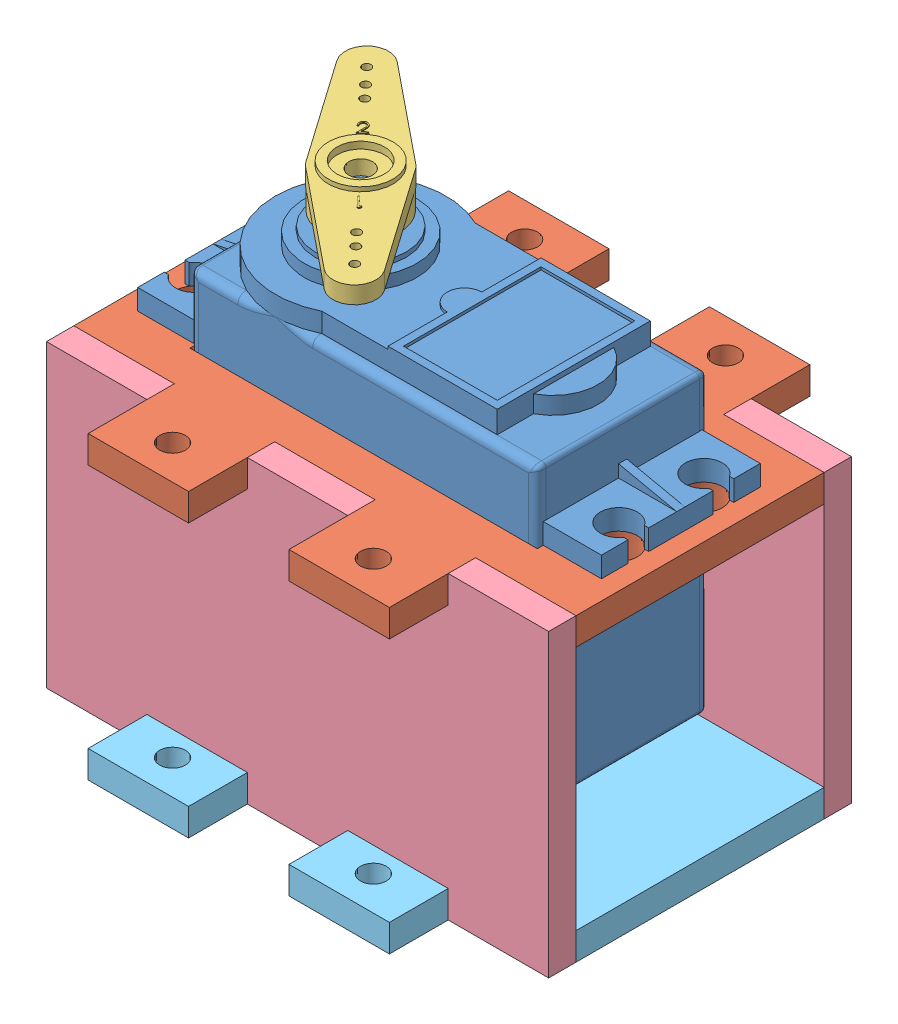
SolidWorks assembly Worm Segment, configuration Default. Lengths in mm.
Overall size (58.28 53.69 48.8).
6 component instances, 5 part files, 14 mates.
Components (placement in the parent):
- Servo-1: Servo [Predeterminado] at (16.062 27.2827 43.9827) size (53.82 44.84 19.95)
- Servo Case Front-1: Servo Case Front [Default] at (-13.078 34.2977 43.9827) x (1 0 0) z (0 1 0) size (58.28 48.8 3.17)
- Servo Horn-1: Servo Horn [Default] at (5.812 53.8327 43.9827) x (-0.731483 0 0.68186) z (-0.68186 0 -0.731483) size (9.1 5 34)
- Servo Case Side-1: Servo Case Side [Default] at (-13.078 20.0577 26.4077) size (58.28 34.83 3.17)
- Servo Case Side-2: Servo Case Side [Default] at (-13.078 20.0577 58.3827) size (58.28 34.83 3.17)
- Servo Case Back-1: Servo Case Back [Default] at (-13.078 5.8177 43.9827) x (1 0 0) z (0 -1 0) size (58.28 48.8 3.17)
Mates (geometry in assembly coordinates):
- Coincident1: coincident anti-aligned: plane of Servo-1 through (36.222 37.4727 53.2027) normal (0 -1 0); plane of Servo Case Front-1 through (-13.078 37.4727 43.9827) normal (0 1 0)
- Concentric4: concentric anti-aligned: cylinder of Servo-1 through (5.812 53.8327 43.9827) axis (0 -1 0) radius 2.92; circle of Servo Horn-1
- Coincident2: coincident anti-aligned: plane of Servo-1 through (5.812 53.8327 43.9827) normal (0 1 0); plane of Servo Horn-1 through (15.699 53.8327 54.5892) normal (0 -1 0)
- Concentric5: concentric anti-aligned: cylinder of Servo-1 through (40.712 31.3133 39.0477) axis (0 1 0) radius 2.15; cylinder of Servo Case Front-1 through (40.712 37.4727 39.0477) axis (0 -1 0) radius 2.15
- Concentric6: concentric anti-aligned: cylinder of Servo-1 through (-8.588 31.3133 48.9177) axis (0 1 0) radius 2.15; cylinder of Servo Case Front-1 through (-8.588 37.4727 48.9177) axis (0 -1 0) radius 2.15
- Coincident4: coincident anti-aligned: plane of Servo Case Front-1 through (45.202 37.4727 29.5827) normal (0 0 -1); plane of Servo Case Side-1 through (-13.078 20.0577 29.5827) normal (0 0 1)
- Coincident8: coincident anti-aligned: plane of Servo Case Front-1 through (-13.078 37.4727 58.3827) normal (0 0 1); plane of Servo Case Side-2 through (-13.078 20.0577 58.3827) normal (0 0 -1)
- Coincident9: coincident aligned: cylinder of Servo Case Front-1 through (4.406 37.4727 64.414) axis (0 -1 0) radius 1.5; circle of Servo Case Back-1
- Concentric7: concentric anti-aligned: cylinder of Servo Case Front-1 through (27.718 37.4727 64.414) axis (0 -1 0) radius 1.5; cylinder of Servo Case Back-1 through (27.718 2.6427 64.414) axis (0 1 0) radius 1.5
- Coincident11: coincident aligned: plane of Servo Case Front-1 through (45.202 37.4727 43.9827) normal (1 0 0); plane of Servo Case Side-2 through (45.202 34.2977 61.5577) normal (1 0 0)
- Coincident14: coincident aligned: plane of Servo Case Side-1 through (45.202 34.2977 29.5827) normal (1 0 0); plane of Servo Case Side-2 through (45.202 34.2977 61.5577) normal (1 0 0)
- Coincident15: coincident aligned: plane of Servo Case Side-1 through (45.202 2.6427 29.5827) normal (0 -1 0); plane of Servo Case Side-2 through (-13.078 2.6427 61.5577) normal (0 -1 0)
- Coincident17: coincident anti-aligned: plane of Servo Case Side-2 through (33.546 5.8177 61.5577) normal (0 -1 0); plane of Servo Case Back-1 through (4.407 5.8177 43.9827) normal (0 1 0)
- Coincident20: coincident aligned: plane of Servo Case Front-1 through (-13.078 37.4727 43.9827) normal (0 1 0); plane of Servo Case Side-1 through (45.202 37.4727 29.5827) normal (0 1 0)
